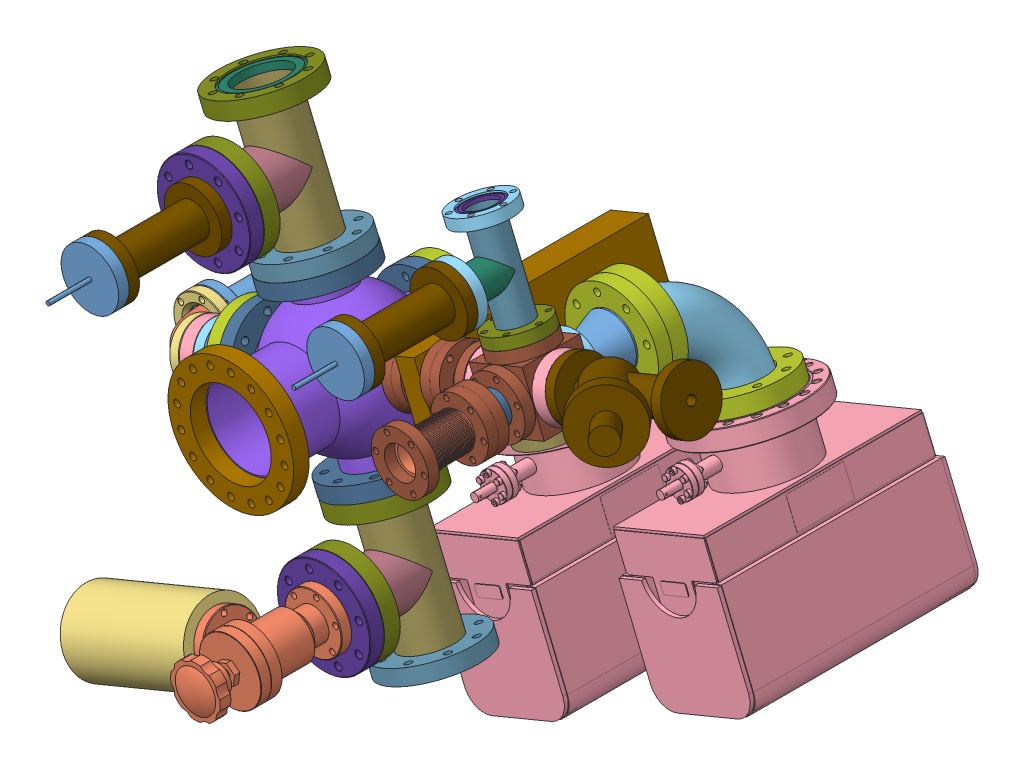
SolidWorks assembly Assem8, configuration Default. Lengths in mm.
Overall size (703.38 642.32 644.93).
103 component instances, 38 part files, 83 mates.
Components (placement in the parent):
- mdc 275 halfnipple-1: mdc 275 halfnipple [Default] at (-24.8274 -18.3346 25.5574) size (69.34 69.34 62.48)
- L275-403502-6: L275-403502 [Default] at (27.1869 1.5159 24.2874) x (-0.923728 -0.383049 0) z (0 0 -1) size (77.27 39.99 77.27)
- 915002-3: 915002 [Default] at (-24.8274 -18.3346 38.2574) x (0 0 -1) z (1 0 0) size (12.7 69.34 69.34)
- mdc 2.75 doublesided_hole-1: mdc 2.75 doublesided_hole [Default] at (43.4775 8.648 79.5644) x (0.146727 -0.353833 -0.923728) z (0.923728 0.383049 0) size (69.34 69.34 19.05)
- 915002-4: 915002 [Default] at (14.1491 -3.5138 79.5644) x (0.923728 0.383049 0) z (0 0 1) size (12.7 69.34 69.34)
- 100014 (2.75 X 1.5 REC)-1: 100014 (2.75 X 1.5 REC) [Default] at (43.4775 8.648 79.5644) x (0.923728 0.383049 0) z (0 0 1) size (12.7 69.34 69.34)
- red1-402032-001-1: red1-402032-001 [Default] at (97.817 31.1814 79.5644) x (-0.923728 -0.383049 0) z (0 0 1) size (60.1 63.5 63.5)
- 110021 (4.5 X 2.5 NR)-1: 110021 (4.5 X 2.5 NR) [Default] at (97.817 31.1814 79.5644) x (-0.923728 -0.383049 0) z (0 0 1) size (17.27 113.54 113.54)
- custom_sixway_cross-1: custom_sixway_cross [Default] at (189.7246 79.077 65.1716) x (-0.923728 -0.383049 0) z (-0.383049 0.923728 0) size (201.17 247.4 209.3)
  - custom_sixway_tube-1: custom_sixway_tube [Default] at (-1.4041 14.3928 -9.0374) size (170.94 210.82 174.24)
  - 6in_CF_flange-3: 6in_CF_flange [Default] at (-1.4041 157.1408 -9.0374) x (1 0 0) z (0 -1 0) size (152.4 152.4 19.05)
  - 4.5in_CF_flange-1: 4.5in_CF_flange [Default] at (85.7179 14.3928 -9.0374) x (0 -1 0) z (0 0 1) size (114.3 17.53 114.3)
  - 4.5in_CF_flange-2: 4.5in_CF_flange [Default] at (-1.4041 14.3928 78.0846) x (1 0 0) z (0 -1 0) size (114.3 17.53 114.3)
  - 4.5in_CF_flange-3: 4.5in_CF_flange [Default] at (-1.4041 14.3928 -113.6854) x (1 0 0) z (0 -1 0) size (114.3 17.53 114.3)
  - 2.75in_CF_flange-1: 2.75in_CF_flange [Default] at (-97.9241 14.3928 -9.0374) x (0 -1 0) z (0 0 1) size (69.85 12.7 69.85)
  - 4.5in_CF_flange-4: 4.5in_CF_flange [Default] at (-1.4041 -90.2552 -9.0374) size (114.3 17.53 114.3)
- T4-404038-1: T4-404038 [Default] at (92.3728 317.5077 79.5644) x (0.923728 0.383049 0) z (0.383049 -0.923728 0) size (113.54 142.49 171.45)
  - 404038-001-1: 404038-001 [Default] at origin size (63.51 63.51 152.4)
  - 404038-002-1: 404038-002 [Default] at (0 0 76.2) x (1 0 0) z (0 1 0) size (63.5 63.5 78.71)
  - 110021 (4.5 X 2.5 NR)_1-1: 110021 (4.5 X 2.5 NR)_1 [Default] at (0 0 161.925) x (0 0 -1) z (1 0 0) size (17.27 113.54 113.54)
  - 100021 (4.5 X 2.5 R)_1-1: 100021 (4.5 X 2.5 R)_1 [Default] at (0 73.025 76.2) x (0 1 0) z (0 0 1) size (19.05 113.54 113.54)
    - 100021 (4.5 X 2.5 INS)_1-1: 100021 (4.5 X 2.5 INS)_1 [Default] at origin size (12.04 82.3 82.3)
    - 100021 (4.5 X 2.5 REC)_1-1: 100021 (4.5 X 2.5 REC)_1 [Default] at (-6.35 0 0) x (1 0 0) z (0 0 -1) size (19.05 113.54 113.54)
  - 100021 (4.5 X 2.5 R)_1-2: 100021 (4.5 X 2.5 R)_1 [Default] at (0 0 3.175) x (0 0 -1) z (1 0 0) size (19.05 113.54 113.54)
    - 100021 (4.5 X 2.5 INS)_1-1: 100021 (4.5 X 2.5 INS)_1 [Default] at origin size (12.04 82.3 82.3)
    - 100021 (4.5 X 2.5 REC)_1-1: 100021 (4.5 X 2.5 REC)_1 [Default] at (-6.35 0 0) x (1 0 0) z (0 0 -1) size (19.05 113.54 113.54)
- zerolength 2.75 to 4.5 mdc-1: zerolength 2.75 to 4.5 mdc [Default] at (121.5611 247.1196 165.2894) x (-0.923728 -0.383049 0) z (0 0 -1) size (113.54 113.54 17.27)
- nipple 2.75 mdc-1: nipple 2.75 mdc [Default] at (121.5611 247.1196 307.7834) x (1 0 0) z (0 1 0) size (69.85 125.22 69.85)
- ion gauge uhv 24p footprint-1: ion gauge uhv 24p footprint [Default] at (121.5611 247.1196 320.4834) x (1 0 0) z (0 1 0) size (69.85 147.62 69.85)
- angle valve 1.5 inch 310029 mdc-1: angle valve 1.5 inch 310029 mdc [Default] at (267.4055 -104.5861 283.2724) x (-0.923728 -0.383049 0) z (-0.383049 0.923728 0) size (100.2 160.92 75.44)
- T4-404038-2: T4-404038 [Default] at (238.2172 -34.1981 79.5644) x (0.923728 0.383049 0) z (0.383049 -0.923728 0) size (113.54 142.49 171.45)
  - 404038-001-1: 404038-001 [Default] at origin size (63.51 63.51 152.4)
  - 404038-002-1: 404038-002 [Default] at (0 0 76.2) x (1 0 0) z (0 1 0) size (63.5 63.5 78.71)
  - 110021 (4.5 X 2.5 NR)_1-1: 110021 (4.5 X 2.5 NR)_1 [Default] at (0 0 161.925) x (0 0 -1) z (1 0 0) size (17.27 113.54 113.54)
  - 100021 (4.5 X 2.5 R)_1-1: 100021 (4.5 X 2.5 R)_1 [Default] at (0 73.025 76.2) x (0 1 0) z (0 0 1) size (19.05 113.54 113.54)
    - 100021 (4.5 X 2.5 INS)_1-1: 100021 (4.5 X 2.5 INS)_1 [Default] at origin size (12.04 82.3 82.3)
    - 100021 (4.5 X 2.5 REC)_1-1: 100021 (4.5 X 2.5 REC)_1 [Default] at (-6.35 0 0) x (1 0 0) z (0 0 -1) size (19.05 113.54 113.54)
  - 100021 (4.5 X 2.5 R)_1-2: 100021 (4.5 X 2.5 R)_1 [Default] at (0 0 3.175) x (0 0 -1) z (1 0 0) size (19.05 113.54 113.54)
    - 100021 (4.5 X 2.5 INS)_1-1: 100021 (4.5 X 2.5 INS)_1 [Default] at origin size (12.04 82.3 82.3)
    - 100021 (4.5 X 2.5 REC)_1-1: 100021 (4.5 X 2.5 REC)_1 [Default] at (-6.35 0 0) x (1 0 0) z (0 0 -1) size (19.05 113.54 113.54)
- zerolength 2.75 to 4.5 mdc-3: zerolength 2.75 to 4.5 mdc [Default] at (267.4055 -104.5861 165.2894) x (-0.923728 -0.383049 0) z (0 0 -1) size (113.54 113.54 17.27)
- turbo pump footpring-1: turbo pump footpring [Default] at (209.6873 -128.5206 245.9852) x (-0.383049 0.923728 0) z (0 0 1) size (91.44 162.05 91.44)
- ion pump gamma vacuum 75S-6S-KG_SW0003-1: ion pump gamma vacuum 75S-6S-KG_SW0003 [Default] at (324.7489 -242.8704 -129.9856) x (0.923728 0.383049 0) z (0 0 1) size (151.64 242.24 276.78)
- L4-403004_1-3: L4-403004_1 [Default] at (231.0174 -16.8357 -129.9856) x (0 0 1) z (-0.923728 -0.383049 0) size (161.67 161.67 113.54)
  - 403004-001_1-1: 403004-001_1 [Default] at origin size (128.92 128.92 67.08)
  - 100021 (4.5 X 2.5 R)_2-1: 100021 (4.5 X 2.5 R)_2 [Default] at (92.202 95.377 0) x (1 0 0) z (0 0 -1) size (19.05 113.54 113.54)
    - 100021 (4.5 X 2.5 INS)_2-1: 100021 (4.5 X 2.5 INS)_2 [Default] at origin size (12.04 82.3 82.3)
    - 100021 (4.5 X 2.5 REC)_2-1: 100021 (4.5 X 2.5 REC)_2 [Default] at (-6.35 0 0) x (1 0 0) z (0 0 -1) size (19.05 113.54 113.54)
  - 100021 (4.5 X 2.5 R)_2-2: 100021 (4.5 X 2.5 R)_2 [Default] at (0 3.175 0) x (0 -1 0) z (0 0 -1) size (19.05 113.54 113.54)
    - 100021 (4.5 X 2.5 INS)_2-1: 100021 (4.5 X 2.5 INS)_2 [Default] at origin size (12.04 82.3 82.3)
    - 100021 (4.5 X 2.5 REC)_2-1: 100021 (4.5 X 2.5 REC)_2 [Default] at (-6.35 0 0) x (1 0 0) z (0 0 -1) size (19.05 113.54 113.54)
- zerolength 6 45 mdc-1: zerolength 6 45 mdc [Default] at (242.2549 -43.9351 -129.9856) x (0.853273 0.353833 -0.383049) z (0.383049 -0.923728 0) size (151.64 151.64 19.81)
- gatevalve-1: gatevalve [Default] at (298.9549 11.514 55.3656) x (0.383049 -0.923728 0) z (0.923728 0.383049 0) size (88.9 280.54 50.84)
  - gatevalve_body-1: gatevalve_body [Default] at (-95.213 2.8522 48.3049) size (88.9 277.88 50.04)
  - 2.75in_CF_flange-3: 2.75in_CF_flange [Default] at (-95.213 -24.1988 73.7492) x (1 0 0) z (0 1 0) size (69.85 12.7 69.85)
  - 2.75in_CF_flange-4: 2.75in_CF_flange [Default] at (-95.213 -24.1988 35.6049) x (-1 0 0) z (0 -1 0) size (69.85 12.7 69.85)
- minilength_nipple-1: minilength_nipple [Default] at (349.6703 127.2966 78.7528) x (0.383049 -0.923728 0) z (0 0 1) size (69.85 44.45 69.85)
  - minilength_nipple_tube-1: minilength_nipple_tube [Default] at (-7.6879 4.7765 0.8117) size (38.1 19.05 38.1)
  - 2.75in_CF_flange-3: 2.75in_CF_flange [Default] at (-7.6879 14.3015 0.8117) size (69.85 12.7 69.85)
  - 2.75in_CF_flange-4: 2.75in_CF_flange [Default] at (-7.6879 -17.4485 0.8117) size (69.85 12.7 69.85)
- mdc 2.75 doublesided_hole-4: mdc 2.75 doublesided_hole [Default] at (371.6676 144.741 79.5644) x (0.146727 -0.353833 0.923728) z (-0.923728 -0.383049 0) size (69.34 69.34 19.05)
- mdc 2.75 doublesided_hole-5: mdc 2.75 doublesided_hole [Default] at (453.787 178.7941 79.5644) x (0.146727 -0.353833 0.923728) z (-0.923728 -0.383049 0) size (69.34 69.34 19.05)
- six way cube-1: six way cube [Default] at (421.5258 165.4161 79.5644) x (0 0 1) z (-0.923728 -0.383049 0) size (69.85 69.85 69.85)
- 2.75in  window mdc-1: 2.75in  window mdc [Default] at (439.7685 121.4235 79.5644) x (0.853273 0.353833 0.383049) z (-0.383049 0.923728 0) size (69.34 69.34 12.7)
  - Part3^2.75in  window mdc-1: Part3^2.75in  window mdc [Default] at origin size (69.34 69.34 12.7) (virtual)
  - Part4^2.75in  window mdc-1: Part4^2.75in  window mdc [Default] at (0 0 12.7) size (38.1 38.1 2.67) (virtual)
- T275-404002_a-1: T275-404002_a [Default] at (357.4671 319.8944 79.5644) x (0.923728 0.383049 0) z (0.383049 -0.923728 0) size (69.34 97.13 124.92)
  - 404002-001-1: 404002-001 [Default] at origin size (38.1 38.1 114.3)
  - 404002-002-1: 404002-002 [Default] at (0 0 57.15) x (-1 0 0) z (0 1 0) size (38.1 38.1 58.53)
  - 110014 (2.75 X 1.5 NR)_1-1: 110014 (2.75 X 1.5 NR)_1 [Default] at (0 0 113.2586) x (0 0 1) z (-1 0 0) size (12.7 69.34 69.34)
  - 100014 (2.75 X 1.5 R)-1: 100014 (2.75 X 1.5 R) [Default] at (0 62.4586 57.15) x (0 -1 0) z (1 0 0) size (12.7 69.34 69.34)
    - 100014 (2.75 X 1.5 REC)-1: 100014 (2.75 X 1.5 REC) [Default] at origin size (12.7 69.34 69.34)
    - 100014 (2.75 X 1.5 INS)-1: 100014 (2.75 X 1.5 INS) [Default] at (1.17 0 0) x (1 0 0) z (0 0.994423 -0.105464) size (6.96 48.1 48.1)
  - 100014 (2.75 X 1.5 R)-2: 100014 (2.75 X 1.5 R) [Default] at (0 0 -5.3086) x (0 0 1) z (-1 0 0) size (12.7 69.34 69.34)
    - 100014 (2.75 X 1.5 REC)-1: 100014 (2.75 X 1.5 REC) [Default] at origin size (12.7 69.34 69.34)
    - 100014 (2.75 X 1.5 INS)-1: 100014 (2.75 X 1.5 INS) [Default] at (1.17 0 0) x (1 0 0) z (0 0.994423 -0.105464) size (6.96 48.1 48.1)
- 2.75in_CF_flange-1: 2.75in_CF_flange [Default] at (403.2831 209.4086 79.5644) x (-0.923728 -0.383049 0) z (0 0 1) size (69.85 12.7 69.85)
- nipple 2.75 mdc-2: nipple 2.75 mdc [Default] at (379.3584 267.1034 142.023) x (1 0 0) z (0 -1 0) size (69.85 125.22 69.85)
- ion gauge uhv 24p footprint-2: ion gauge uhv 24p footprint [Default] at (379.3584 267.1034 279.945) x (1 0 0) z (0 1 0) size (69.85 147.62 69.85)
- valve mdc inline all metal small-1: valve mdc inline all metal small [Default] at (470.2109 185.6047 79.5644) x (-0.383049 0.923728 0) z (0 0 -1) size (75.44 172.37 161.4)
- 402032-1: 402032 [Default] at (421.5258 165.4161 -20.7656) x (0 0 1) z (-1 0 0) size (74.93 113.54 113.54)
  - 402032-001-1: 402032-001 [Default] at origin size (60.1 63.5 63.5)
  - 110021 (4.5 X 2.5 NR)-1: 110021 (4.5 X 2.5 NR) [Default] at (-9.525 0 0) size (17.27 113.54 113.54)
  - 100014 (2.75 X 1.5 R)-1: 100014 (2.75 X 1.5 R) [Default] at (65.405 0 0) x (-1 0 0) z (0 0 -1) size (12.7 69.34 69.34)
    - 100014 (2.75 X 1.5 REC)-1: 100014 (2.75 X 1.5 REC) [Default] at origin size (12.7 69.34 69.34)
    - 100014 (2.75 X 1.5 INS)-1: 100014 (2.75 X 1.5 INS) [Default] at (1.17 0 0) x (1 0 0) z (0 0.994423 -0.105464) size (6.96 48.1 48.1)
- L4-403004_1-4: L4-403004_1 [Default] at (421.5258 165.4161 -39.8156) x (0.383049 -0.923728 0) z (0.923728 0.383049 0) size (161.67 161.67 113.54)
  - 403004-001_1-1: 403004-001_1 [Default] at origin size (128.92 128.92 67.08)
  - 100021 (4.5 X 2.5 R)_2-1: 100021 (4.5 X 2.5 R)_2 [Default] at (92.202 95.377 0) x (1 0 0) z (0 0 -1) size (19.05 113.54 113.54)
    - 100021 (4.5 X 2.5 INS)_2-1: 100021 (4.5 X 2.5 INS)_2 [Default] at origin size (12.04 82.3 82.3)
    - 100021 (4.5 X 2.5 REC)_2-1: 100021 (4.5 X 2.5 REC)_2 [Default] at (-6.35 0 0) x (1 0 0) z (0 0 -1) size (19.05 113.54 113.54)
  - 100021 (4.5 X 2.5 R)_2-2: 100021 (4.5 X 2.5 R)_2 [Default] at (0 3.175 0) x (0 -1 0) z (0 0 -1) size (19.05 113.54 113.54)
    - 100021 (4.5 X 2.5 INS)_2-1: 100021 (4.5 X 2.5 INS)_2 [Default] at origin size (12.04 82.3 82.3)
    - 100021 (4.5 X 2.5 REC)_2-1: 100021 (4.5 X 2.5 REC)_2 [Default] at (-6.35 0 0) x (1 0 0) z (0 0 -1) size (19.05 113.54 113.54)
- ion pump gamma vacuum 75S-6S-KG_SW0003-2: ion pump gamma vacuum 75S-6S-KG_SW0003 [Default] at (545.1364 -132.6726 -135.1926) x (0.923728 0.383049 0) z (0 0 1) size (151.64 242.24 276.78)
- minilength_nipple-2: minilength_nipple [Default] at (429.2137 166.2277 131.9379) x (1 0 0) z (0 -1 0) size (69.85 44.45 69.85)
  - minilength_nipple_tube-1: minilength_nipple_tube [Default] at (-7.6879 4.7765 0.8117) size (38.1 19.05 38.1)
  - 2.75in_CF_flange-3: 2.75in_CF_flange [Default] at (-7.6879 14.3015 0.8117) size (69.85 12.7 69.85)
  - 2.75in_CF_flange-4: 2.75in_CF_flange [Default] at (-7.6879 -17.4485 0.8117) size (69.85 12.7 69.85)
- Bellow_2.75in_CF-1: Bellow_2.75in_CF [Default] at (449.3378 155.3944 206.3015) x (1 0 0) z (0 1 0) size (96.68 84.96 96.68)
  - 2.75in_bellow_tube-1: 2.75in_bellow_tube [Default] at (-27.8121 6.8508 10.0217) size (43.18 63.5 43.18)
  - 2.75in_CF_flange-1: 2.75in_CF_flange [Default] at (-27.8121 47.3621 10.0217) x (-0.837169 0 -0.546944) z (-0.546944 0 0.837169) size (69.85 12.7 69.85)
  - 2.75in_CF_flange-2: 2.75in_CF_flange [Default] at (-27.8121 -24.8992 10.0217) x (-0.837169 0 -0.546944) z (-0.546944 0 0.837169) size (69.85 12.7 69.85)
Mates (geometry in assembly coordinates):
- Coincident9: coincident anti-aligned: plane of mdc 275 halfnipple-1 through (-24.8274 -18.3346 24.2874) normal (0 0 1); plane of L275-403502-6 through (-25.6042 -20.3753 24.2874) normal (0 0 -1)
- Tangent4: tangent: cylinder of mdc 275 halfnipple-1 through (-24.8274 -18.3346 24.2874) axis (0 0 -1) radius 17.4625; face of L275-403502-6
- Coincident12: coincident anti-aligned: plane of mdc 275 halfnipple-1 through (-24.8274 -18.3346 25.5574) normal (0 0 1); plane of 915002-3 through (-24.8274 -18.3346 25.5574) normal (0 0 -1)
- Coincident14: coincident anti-aligned: plane of mdc 275 halfnipple-1 through (-24.8274 -18.3346 25.5574) normal (0 0 1); plane of 915002-3 through (-24.8274 -18.3346 25.5574) normal (0 0 -1)
- Coincident15: coincident aligned: circle of mdc 275 halfnipple-1; circle of 915002-3
- Coincident16: coincident anti-aligned: plane of L275-403502-6 through (27.1869 1.5159 81.4374) normal (0.923728 0.383049 0); plane of mdc 2.75 doublesided_hole-1 through (27.0536 1.8374 79.5644) normal (-0.923728 -0.383049 0)
- Tangent6: tangent: face of L275-403502-6; cylinder of mdc 2.75 doublesided_hole-1 through (27.6508 2.0851 79.5644) axis (0.923728 0.383049 0) radius 20.955
- Coincident17: coincident anti-aligned: plane of mdc 2.75 doublesided_hole-1 through (25.8804 1.3509 79.5644) normal (-0.923728 -0.383049 0); plane of 915002-4 through (25.8804 1.3509 79.5644) normal (0.923728 0.383049 0)
- Coincident18: coincident anti-aligned: circle of 915002-4; circle of mdc 2.75 doublesided_hole-1
- Coincident19: coincident anti-aligned: plane of mdc 2.75 doublesided_hole-1 through (42.3043 8.1616 79.5644) normal (0.923728 0.383049 0); plane of red1-402032-001-1 through (49.2852 -8.6729 79.5644) normal (-0.923728 -0.383049 0)
- Concentric1: concentric anti-aligned: cylinder of mdc 2.75 doublesided_hole-1 through (41.7071 7.9139 79.5644) axis (0.923728 0.383049 0) radius 20.955; cylinder of red1-402032-001-1 through (48.17 10.5939 79.5644) axis (-0.923728 -0.383049 0) radius 19.05
- Coincident20: coincident anti-aligned: plane of mdc 2.75 doublesided_hole-1 through (43.4775 8.648 79.5644) normal (0.923728 0.383049 0); plane of 100014 (2.75 X 1.5 REC)-1 through (32.2261 35.7809 79.5644) normal (-0.923728 -0.383049 0)
- Concentric2: concentric anti-aligned: cylinder of 100014 (2.75 X 1.5 REC)-1 through (46.9969 10.1074 79.5644) axis (0.923728 0.383049 0) radius 24.0754; cylinder of red1-402032-001-1 through (48.17 10.5939 79.5644) axis (-0.923728 -0.383049 0) radius 19.05
- Coincident22: coincident anti-aligned: plane of red1-402032-001-1 through (109.6626 2.6156 79.5644) normal (0.923728 0.383049 0); plane of custom_sixway_cross-1/4.5in_CF_flange-1 through (97.817 31.1814 79.5644) normal (-0.923728 -0.383049 0)
- Coincident23: coincident aligned: circle of red1-402032-001-1; circle of custom_sixway_cross-1/4.5in_CF_flange-1
- Coincident24: coincident anti-aligned: plane of 110021 (4.5 X 2.5 NR)-1 through (116.5949 -14.1016 79.5644) normal (0.923728 0.383049 0); plane of custom_sixway_cross-1/4.5in_CF_flange-1 through (97.817 31.1814 79.5644) normal (-0.923728 -0.383049 0)
- Concentric3: concentric aligned: cylinder of red1-402032-001-1 through (93.4178 29.3571 79.5644) axis (-0.923728 -0.383049 0) radius 31.75; cylinder of 110021 (4.5 X 2.5 NR)-1 through (92.8774 29.1331 79.5644) axis (-0.923728 -0.383049 0) radius 30.1625
- Parallel6: parallel aligned: plane of mdc 275 halfnipple-1 through (-24.8274 -18.3346 -36.9266) normal (0 0 -1); plane of custom_sixway_cross-1/4.5in_CF_flange-4 through (194.4833 71.2667 -25.0836) normal (0 0 -1)
- Coincident26: coincident anti-aligned: plane of custom_sixway_cross-1/4.5in_CF_flange-2 through (154.398 167.933 79.5644) normal (-0.383049 0.923728 0); plane of T4-404038-1/110021 (4.5 X 2.5 NR)_1-1 through (154.398 167.933 128.5864) normal (0.383049 -0.923728 0)
- Concentric4: concentric aligned: circle of custom_sixway_cross-1/4.5in_CF_flange-2; circle of T4-404038-1/110021 (4.5 X 2.5 NR)_1-1
- Parallel7: parallel aligned: plane of custom_sixway_cross-1/6in_CF_flange-3 through (194.4833 71.2667 222.3124) normal (0 0 1); plane of T4-404038-1/100021 (4.5 X 2.5 R)_1-1/100021 (4.5 X 2.5 REC)_1-1 through (166.8441 265.8974 165.2894) normal (0 0 1)
- Coincident28: coincident anti-aligned: plane of T4-404038-1/100021 (4.5 X 2.5 R)_1-1/100021 (4.5 X 2.5 REC)_1-1 through (166.8441 265.8974 165.2894) normal (0 0 1); plane of zerolength 2.75 to 4.5 mdc-1 through (121.5611 247.1196 165.2894) normal (0 0 -1)
- Concentric5: concentric aligned: circle of T4-404038-1/100021 (4.5 X 2.5 R)_1-1/100021 (4.5 X 2.5 INS)_1-1; circle of zerolength 2.75 to 4.5 mdc-1
- Coincident29: coincident anti-aligned: plane of zerolength 2.75 to 4.5 mdc-1 through (121.5611 247.1196 182.5614) normal (0 0 1); plane of nipple 2.75 mdc-1 through (121.5611 247.1196 182.5614) normal (0 0 -1)
- Concentric6: concentric aligned: circle of zerolength 2.75 to 4.5 mdc-1; circle of nipple 2.75 mdc-1
- Coincident30: coincident anti-aligned: plane of nipple 2.75 mdc-1 through (121.5611 247.1196 307.7834) normal (0 0 1); plane of ion gauge uhv 24p footprint-1 through (121.5611 247.1196 307.7834) normal (0 0 -1)
- Concentric7: concentric aligned: cylinder of nipple 2.75 mdc-1 through (121.5611 247.1196 182.5614) axis (0 0 1) radius 17.526; cylinder of ion gauge uhv 24p footprint-1 through (121.5611 247.1196 223.6586) axis (0 0 1) radius 16.637
- Coincident33: coincident anti-aligned: plane of custom_sixway_cross-1/4.5in_CF_flange-3 through (234.5687 -25.3996 79.5644) normal (0.383049 -0.923728 0); plane of T4-404038-2/100021 (4.5 X 2.5 R)_1-2/100021 (4.5 X 2.5 REC)_1-1 through (234.5687 -25.3996 30.5424) normal (-0.383049 0.923728 0)
- Concentric9: concentric anti-aligned: circle of custom_sixway_cross-1/4.5in_CF_flange-3; circle of T4-404038-2/100021 (4.5 X 2.5 R)_1-2/100021 (4.5 X 2.5 INS)_1-1
- Parallel8: parallel aligned: plane of custom_sixway_cross-1/6in_CF_flange-3 through (194.4833 71.2667 222.3124) normal (0 0 1); plane of T4-404038-2/100021 (4.5 X 2.5 R)_1-1/100021 (4.5 X 2.5 REC)_1-1 through (312.6885 -85.8083 165.2894) normal (0 0 1)
- Coincident35: coincident anti-aligned: plane of T4-404038-2/100021 (4.5 X 2.5 R)_1-1/100021 (4.5 X 2.5 REC)_1-1 through (312.6885 -85.8083 165.2894) normal (0 0 1); plane of zerolength 2.75 to 4.5 mdc-3 through (267.4055 -104.5861 165.2894) normal (0 0 -1)
- Concentric10: concentric aligned: circle of T4-404038-2/100021 (4.5 X 2.5 R)_1-1/100021 (4.5 X 2.5 INS)_1-1; circle of zerolength 2.75 to 4.5 mdc-3
- Coincident36: coincident anti-aligned: plane of angle valve 1.5 inch 310029 mdc-1 through (267.4055 -104.5861 182.5614) normal (0 0 -1); plane of zerolength 2.75 to 4.5 mdc-3 through (267.4055 -104.5861 182.5614) normal (0 0 1)
- Concentric11: concentric anti-aligned: circle of angle valve 1.5 inch 310029 mdc-1; circle of zerolength 2.75 to 4.5 mdc-3
- Parallel9: parallel anti-aligned: plane of angle valve 1.5 inch 310029 mdc-1 through (209.6873 -128.5206 245.9852) normal (-0.923728 -0.383049 0); plane of custom_sixway_cross-1/4.5in_CF_flange-1 through (114.0063 37.8947 79.5644) normal (0.923728 0.383049 0)
- Coincident38: coincident anti-aligned: plane of angle valve 1.5 inch 310029 mdc-1 through (209.6873 -128.5206 245.9852) normal (-0.923728 -0.383049 0); plane of turbo pump footpring-1 through (209.6873 -128.5206 245.9852) normal (0.923728 0.383049 0)
- Concentric12: concentric aligned: circle of angle valve 1.5 inch 310029 mdc-1; circle of turbo pump footpring-1
- Coincident43: coincident anti-aligned: plane of custom_sixway_cross-1/4.5in_CF_flange-4 through (194.4833 71.2667 -25.0836) normal (0 0 -1); plane of L4-403004_1-3/100021 (4.5 X 2.5 R)_2-1/100021 (4.5 X 2.5 REC)_2-1 through (175.7055 116.5497 -25.0836) normal (0 0 1)
- Concentric14: concentric anti-aligned: circle of custom_sixway_cross-1/4.5in_CF_flange-4; circle of L4-403004_1-3/100021 (4.5 X 2.5 R)_2-1/100021 (4.5 X 2.5 INS)_2-1
- Parallel11: parallel aligned: plane of T4-404038-2/110021 (4.5 X 2.5 NR)_1-1 through (300.2424 -183.7727 128.5864) normal (0.383049 -0.923728 0); plane of L4-403004_1-3/100021 (4.5 X 2.5 R)_2-2/100021 (4.5 X 2.5 REC)_2-1 through (234.6659 -25.6342 -80.9636) normal (0.383049 -0.923728 0)
- Coincident45: coincident anti-aligned: plane of L4-403004_1-3/100021 (4.5 X 2.5 R)_2-2/100021 (4.5 X 2.5 REC)_2-1 through (234.6659 -25.6342 -80.9636) normal (0.383049 -0.923728 0); plane of zerolength 6 45 mdc-1 through (234.6659 -25.6342 -129.9856) normal (-0.383049 0.923728 0)
- Concentric15: concentric aligned: circle of L4-403004_1-3/100021 (4.5 X 2.5 R)_2-2/100021 (4.5 X 2.5 INS)_2-1; circle of zerolength 6 45 mdc-1
- Coincident46: coincident anti-aligned: plane of ion pump gamma vacuum 75S-6S-KG_SW0003-1 through (241.7684 -42.7619 -129.9856) normal (-0.383049 0.923728 0); plane of zerolength 6 45 mdc-1 through (241.7684 -42.7619 -129.9856) normal (0.383049 -0.923728 0)
- Concentric16: concentric anti-aligned: circle of ion pump gamma vacuum 75S-6S-KG_SW0003-1; circle of zerolength 6 45 mdc-1
- Parallel12: parallel aligned: plane of T4-404038-2/110021 (4.5 X 2.5 NR)_1-1 through (300.2424 -183.7727 128.5864) normal (0.383049 -0.923728 0); plane of ion pump gamma vacuum 75S-6S-KG_SW0003-1 through (297.2543 -280.47 -263.4856) normal (0.383049 -0.923728 0)
- Coincident48: coincident anti-aligned: plane of custom_sixway_cross-1/2.75in_CF_flange-1 through (283.6416 108.2386 79.5644) normal (0.923728 0.383049 0); plane of gatevalve-1/2.75in_CF_flange-4 through (283.6416 108.2386 79.5644) normal (-0.923728 -0.383049 0)
- Coincident49: coincident aligned: circle of custom_sixway_cross-1/2.75in_CF_flange-1; circle of gatevalve-1/2.75in_CF_flange-4
- Parallel13: parallel aligned: plane of ion pump gamma vacuum 75S-6S-KG_SW0003-1 through (285.1991 -147.4955 -262.9356) normal (0 0 -1); plane of gatevalve-1/gatevalve_body-1 through (301.02 67.3249 -166.0536) normal (0 0 -1)
- Coincident51: coincident anti-aligned: plane of gatevalve-1/2.75in_CF_flange-3 through (330.6079 127.7145 79.5644) normal (0.923728 0.383049 0); plane of minilength_nipple-1/2.75in_CF_flange-4 through (330.6079 127.7145 79.5644) normal (-0.923728 -0.383049 0)
- Coincident52: coincident anti-aligned: circle of gatevalve-1/2.75in_CF_flange-3; circle of minilength_nipple-1/2.75in_CF_flange-4
- Coincident53: coincident anti-aligned: plane of minilength_nipple-1/2.75in_CF_flange-3 through (371.6676 144.741 79.5644) normal (0.923728 0.383049 0); plane of mdc 2.75 doublesided_hole-4 through (371.6676 144.741 79.5644) normal (-0.923728 -0.383049 0)
- Concentric17: concentric aligned: circle of minilength_nipple-1/2.75in_CF_flange-3; circle of mdc 2.75 doublesided_hole-4
- Coincident54: coincident anti-aligned: plane of mdc 2.75 doublesided_hole-4 through (389.2646 152.0381 79.5644) normal (0.923728 0.383049 0); plane of six way cube-1 through (375.8866 184.2993 44.6394) normal (-0.923728 -0.383049 0)
- Concentric18: concentric anti-aligned: circle of mdc 2.75 doublesided_hole-4; circle of six way cube-1
- Parallel14: parallel aligned: plane of custom_sixway_cross-1/6in_CF_flange-3 through (194.4833 71.2667 222.3124) normal (0 0 1); plane of six way cube-1 through (402.6426 119.7769 114.4894) normal (0 0 1)
- Coincident56: coincident anti-aligned: plane of mdc 2.75 doublesided_hole-5 through (453.787 178.7941 79.5644) normal (-0.923728 -0.383049 0); plane of six way cube-1 through (440.409 211.0553 44.6394) normal (0.923728 0.383049 0)
- Coincident57: coincident aligned: circle of mdc 2.75 doublesided_hole-5; circle of six way cube-1
- Coincident58: coincident anti-aligned: plane of six way cube-1 through (402.6426 119.7769 44.6394) normal (0.383049 -0.923728 0); plane of 2.75in  window mdc-1/Part3^2.75in  window mdc-1 through (434.9038 133.1549 79.5644) normal (-0.383049 0.923728 0)
- Concentric19: concentric aligned: circle of six way cube-1; circle of 2.75in  window mdc-1/Part3^2.75in  window mdc-1
- Coincident59: coincident anti-aligned: plane of six way cube-1 through (375.8866 184.2993 44.6394) normal (-0.383049 0.923728 0); plane of 2.75in_CF_flange-1 through (408.1478 197.6773 79.5644) normal (0.383049 -0.923728 0)
- Concentric20: concentric anti-aligned: circle of six way cube-1; circle of 2.75in_CF_flange-1
- Coincident60: coincident anti-aligned: plane of T275-404002_a-1/110014 (2.75 X 1.5 NR)_1-1 through (403.2831 209.4086 50.1539) normal (0.383049 -0.923728 0); plane of 2.75in_CF_flange-1 through (403.2831 209.4086 79.5644) normal (-0.383049 0.923728 0)
- Concentric21: concentric anti-aligned: circle of T275-404002_a-1/110014 (2.75 X 1.5 NR)_1-1; circle of 2.75in_CF_flange-1
- Parallel15: parallel aligned: plane of six way cube-1 through (402.6426 119.7769 114.4894) normal (0 0 1); plane of T275-404002_a-1/100014 (2.75 X 1.5 R)-1/100014 (2.75 X 1.5 REC)-1 through (368.107 294.2362 142.023) normal (0 0 1)
- Coincident62: coincident anti-aligned: plane of T275-404002_a-1/100014 (2.75 X 1.5 R)-1/100014 (2.75 X 1.5 REC)-1 through (368.107 294.2362 142.023) normal (0 0 1); plane of nipple 2.75 mdc-2 through (379.3584 267.1034 142.023) normal (0 0 -1)
- Concentric22: concentric anti-aligned: circle of T275-404002_a-1/100014 (2.75 X 1.5 R)-1/100014 (2.75 X 1.5 REC)-1; circle of nipple 2.75 mdc-2
- Coincident63: coincident anti-aligned: plane of nipple 2.75 mdc-2 through (379.3584 267.1034 267.245) normal (0 0 1); plane of ion gauge uhv 24p footprint-2 through (379.3584 267.1034 267.245) normal (0 0 -1)
- Concentric23: concentric anti-aligned: cylinder of nipple 2.75 mdc-2 through (379.3584 267.1034 267.245) axis (0 0 -1) radius 17.526; cylinder of ion gauge uhv 24p footprint-2 through (379.3584 267.1034 183.1202) axis (0 0 1) radius 16.637
- Coincident65: coincident anti-aligned: plane of mdc 2.75 doublesided_hole-5 through (470.2109 185.6047 79.5644) normal (0.923728 0.383049 0); plane of valve mdc inline all metal small-1 through (470.2109 185.6047 79.5644) normal (-0.923728 -0.383049 0)
- Concentric25: concentric aligned: circle of mdc 2.75 doublesided_hole-5; circle of valve mdc inline all metal small-1
- Angle1: planar angle = 0.785398 rad aligned: plane of valve mdc inline all metal small-1 through (593.8073 236.8573 167.8974) normal (0.653174 0.270857 0.707107); plane of nipple 2.75 mdc-2 through (379.3584 267.1034 154.723) normal (0 0 1)
- Coincident67: coincident anti-aligned: plane of six way cube-1 through (402.6426 119.7769 44.6394) normal (0 0 -1); plane of 402032-1/100014 (2.75 X 1.5 R)-1/100014 (2.75 X 1.5 REC)-1 through (421.5258 194.7893 44.6394) normal (0 0 1)
- Concentric26: concentric aligned: circle of six way cube-1; circle of 402032-1/100014 (2.75 X 1.5 R)-1/100014 (2.75 X 1.5 REC)-1
- Coincident68: coincident anti-aligned: plane of 402032-1/110021 (4.5 X 2.5 NR)-1 through (421.5258 214.4381 -30.2906) normal (0 0 -1); plane of L4-403004_1-4/100021 (4.5 X 2.5 R)_2-2/100021 (4.5 X 2.5 REC)_2-1 through (440.3036 120.1331 -30.2906) normal (0 0 1)
- Concentric27: concentric anti-aligned: circle of 402032-1/110021 (4.5 X 2.5 NR)-1; circle of L4-403004_1-4/100021 (4.5 X 2.5 R)_2-2/100021 (4.5 X 2.5 REC)_2-1
- Parallel16: parallel aligned: plane of 2.75in  window mdc-1/Part3^2.75in  window mdc-1 through (439.7685 121.4235 79.5644) normal (0.383049 -0.923728 0); plane of L4-403004_1-4/100021 (4.5 X 2.5 R)_2-1/100021 (4.5 X 2.5 REC)_2-1 through (461.7084 68.5152 -184.2146) normal (0.383049 -0.923728 0)
- Coincident70: coincident anti-aligned: plane of L4-403004_1-4/100021 (4.5 X 2.5 R)_2-1/100021 (4.5 X 2.5 REC)_2-1 through (461.7084 68.5152 -184.2146) normal (0.383049 -0.923728 0); plane of ion pump gamma vacuum 75S-6S-KG_SW0003-2 through (461.7084 68.5152 -135.1926) normal (-0.383049 0.923728 0)
- Concentric28: concentric anti-aligned: circle of L4-403004_1-4/100021 (4.5 X 2.5 R)_2-1/100021 (4.5 X 2.5 REC)_2-1; circle of ion pump gamma vacuum 75S-6S-KG_SW0003-2
- Parallel17: parallel aligned: plane of ion pump gamma vacuum 75S-6S-KG_SW0003-1 through (345.3158 -124.0821 8.3404) normal (0 0 1); plane of ion pump gamma vacuum 75S-6S-KG_SW0003-2 through (565.7033 -13.8843 3.1334) normal (0 0 1)
- Coincident72: coincident: plane of six way cube-1 through (402.6426 119.7769 114.4894) normal (0 0 1); plane of ? through (519.6196 334.0948 114.4894) normal (0 0 -1)
- Concentric29: concentric aligned: circle of six way cube-1; circle of minilength_nipple-2/2.75in_CF_flange-4
- Coincident74: coincident: plane of minilength_nipple-2/2.75in_CF_flange-3 through (421.5258 165.4161 158.9394) normal (0 0 1); plane of Bellow_2.75in_CF-1/2.75in_CF_flange-1 through (421.5258 165.4161 158.9394) normal (0 0 -1)
- Coincident75: coincident aligned: circle of minilength_nipple-2/2.75in_CF_flange-3; circle of Bellow_2.75in_CF-1/2.75in_CF_flange-1
